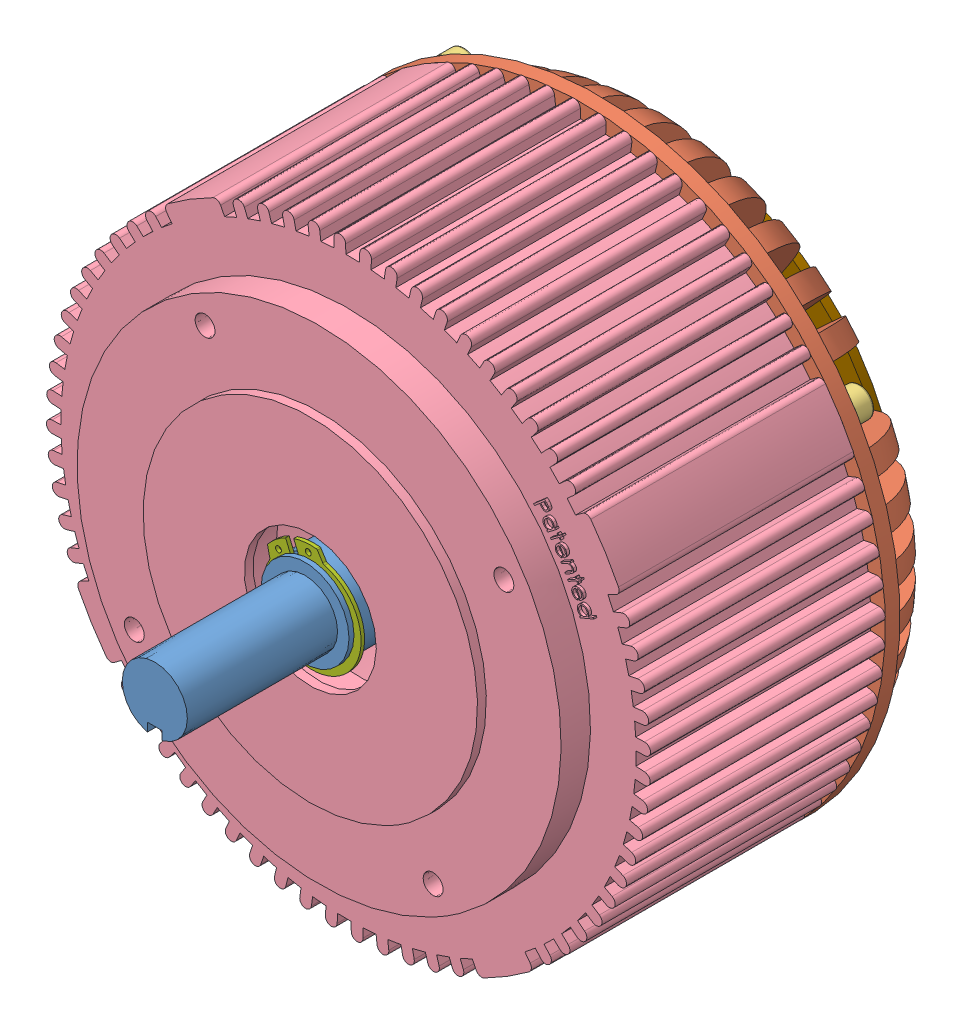
SolidWorks assembly （外形图）风冷图, configuration 默认. Lengths in mm.
Overall size (283.49 283.49 182).
24 component instances, 9 part files, 24 mates.
Components (placement in the parent):
- 普通轴-1: 普通轴 [默认] at (-0.2455 -4.4538 -85) size (35 35 168.2)
- 盖-1: 盖 [默认] at (-0.2455 -4.4538 -43.6) x (0.973109 -0.230344 0) z (0 0 -1) size (206 206 49.2)
- Hexagon socket head cap screws GB-5: Hexagon socket head cap screws GB [GB_FASTENER_SCREWS_HSHCS M8X16-N] at (-54.7076 -38.0675 -75.8) x (0 0 1) z (0.923728 0.383049 0) size (24 13 13)
- Hexagon socket head cap screws GB-6: Hexagon socket head cap screws GB [GB_FASTENER_SCREWS_HSHCS M8X16-N] at (-33.8592 50.0083 -75.8) x (0 0 1) z (0.383049 -0.923728 0) size (24 13 13)
- Hexagon socket head cap screws GB-7: Hexagon socket head cap screws GB [GB_FASTENER_SCREWS_HSHCS M8X16-N] at (54.2166 29.1599 -75.8) x (0 0 1) z (-0.923728 -0.383049 0) size (24 13 13)
- Hexagon socket head cap screws GB-8: Hexagon socket head cap screws GB [GB_FASTENER_SCREWS_HSHCS M8X16-N] at (33.3682 -58.9159 -75.8) x (0 0 1) z (-0.383049 0.923728 0) size (24 13 13)
- 机壳-1: 机壳 [默认] at (-0.2455 -4.4538 30.2) x (0.525214 -0.85097 0) z (0 0 -1) size (206 206 93)
- Hexagon socket head cap screws GB-10: Hexagon socket head cap screws GB [GB_FASTENER_SCREWS_HSHCS M6X16-N] at (51.2255 -87.8488 -73.8) x (0 0 1) z (0.923728 0.383049 0) size (22 10 10)
- Hexagon socket head cap screws GB-11: Hexagon socket head cap screws GB [GB_FASTENER_SCREWS_HSHCS M6X16-N] at (-83.6405 -55.9248 -73.8) x (0 0 1) z (0.383049 -0.923728 0) size (22 10 10)
- Hexagon socket head cap screws GB-12: Hexagon socket head cap screws GB [GB_FASTENER_SCREWS_HSHCS M6X16-N] at (-51.7165 78.9413 -73.8) x (0 0 1) z (-0.923728 -0.383049 0) size (22 10 10)
- Hexagon socket head cap screws GB-13: Hexagon socket head cap screws GB [GB_FASTENER_SCREWS_HSHCS M6X16-N] at (83.1496 47.0172 -73.8) x (0 0 1) z (-0.383049 0.923728 0) size (22 10 10)
- Prevailing torque type 2 GB-1: Prevailing torque type 2 GB [GB_HEXAGON_LOCK_TYPE10 M10-N] at (19.2694 -84.6125 -74.23) x (0.923728 0.383049 0) z (0 0 -1) size (18.48 16 12.8)
- Prevailing torque type 2 GB-2: Prevailing torque type 2 GB [GB_HEXAGON_LOCK_TYPE10 M10-N] at (-6.4561 -86.7197 -74.23) x (0.996886 0.078854 0) z (0 0 -1) size (18.48 16 12.8)
- Prevailing torque type 2 GB-3: Prevailing torque type 2 GB [GB_HEXAGON_LOCK_TYPE10 M10-N] at (-31.5737 -80.7741 -74.23) x (0.972462 -0.233061 0) z (0 0 -1) size (18.48 16 12.8)
- Prevailing torque type 2 GB-4: Prevailing torque type 2 GB [GB_HEXAGON_LOCK_TYPE10 M10-N] at (-53.6247 -67.3578 -74.23) x (0.852847 -0.522161 0) z (0 0 -1) size (18.48 16 12.8)
- Circlips for holes--Type A GB-1: Circlips for holes--Type A GB [GB_CONNECTING_PIECE_RING_RRH 52] at (-0.2455 -4.4538 -64.1) x (-0.923728 -0.383049 0) z (0 0 -1) size (56.2 54.06 2)
- Circlips for shaft--Type A large GB-1: Circlips for shaft--Type A large GB [GB_CONNECTING_PIECE_RING_RRA 30] at (0.1108 -5.3128 28.8) x (0.923728 0.383049 0) z (0 0 -1) size (33.5 36.57 1.2)
- Hexagon socket head cap screws GB-14: Hexagon socket head cap screws GB [GB_FASTENER_SCREWS_HSHCS M3X8-N] at (67.8722 -20.5779 -98.8) x (0 0 1) z (-1 0 0) size (11 5.5 5.5)
- 风页-1: 风页 [默认] at (-0.2455 -4.4538 -63.7) x (0 0 1) z (-1 0 0) size (25.28 108.45 96.5)
- 风页盖板-1: 风页盖板 [默认] at (-0.2455 -4.4538 -92.8) x (-0.230344 -0.973109 0) z (0 0 -1) size (150 150 3)
- Hexagon socket head cap screws GB-15: Hexagon socket head cap screws GB [GB_FASTENER_SCREWS_HSHCS M3X8-N] at (-16.3696 -72.5714 -98.8) x (0 0 1) z (0 1 0) size (11 5.5 5.5)
- Hexagon socket head cap screws GB-16: Hexagon socket head cap screws GB [GB_FASTENER_SCREWS_HSHCS M3X8-N] at (-68.3631 11.6703 -98.8) x (0 0 1) z (1 0 0) size (11 5.5 5.5)
- Hexagon socket head cap screws GB-17: Hexagon socket head cap screws GB [GB_FASTENER_SCREWS_HSHCS M3X8-N] at (15.8786 63.6639 -98.8) x (0 0 1) z (0 -1 0) size (11 5.5 5.5)
- Hexagon socket head cap screws GB-18: Hexagon socket head cap screws GB [GB_FASTENER_SCREWS_HSHCS M4X12-N] at (-18.3654 24.9047 7.2) x (0 0 1) z (-1 0 0) size (16 7 7)
Mates (geometry in assembly coordinates):
- 同心3: concentric anti-aligned: circle of 普通轴-1; circle of 盖-1
- 同心4: concentric anti-aligned: circle of 普通轴-1; circle of 盖-1
- 重合3: coincident aligned: plane of 普通轴-1 through (-0.2455 -4.4538 -45.6) normal (0 0 -1); plane of 盖-1 through (-0.2455 -4.4538 -45.6) normal (0 0 -1)
- 同心7: concentric aligned: cylinder of 盖-1 through (-54.7076 -38.0675 -43.6) axis (0 0 -1) radius 4.5; cylinder of Hexagon socket head cap screws GB-5 through (-54.7076 -38.0675 -51.8) axis (0 0 -1) radius 4
- 重合8: coincident anti-aligned: plane of 盖-1 through (51.9831 216.1904 -67.8) normal (0 0 -1); plane of Hexagon socket head cap screws GB-5 through (-54.7076 -38.0675 -67.8) normal (0 0 1)
- 同心9: concentric anti-aligned: circle of 盖-1; circle of 机壳-1
- 重合10: coincident anti-aligned: circle of 盖-1; plane of 机壳-1 through (-0.2455 -4.4538 -62.8) normal (0 0 -1)
- 同心10: concentric aligned: circle of 盖-1; circle of 机壳-1
- 同心13: concentric aligned: circle of 盖-1; circle of Hexagon socket head cap screws GB-10
- 重合16: coincident anti-aligned: plane of 盖-1 through (51.9831 216.1904 -67.8) normal (0 0 -1); plane of Hexagon socket head cap screws GB-10 through (51.2255 -87.8488 -67.8) normal (0 0 1)
- 同心15: concentric aligned: circle of 盖-1; circle of Prevailing torque type 2 GB-1
- 重合18: coincident anti-aligned: plane of 盖-1 through (51.9831 216.1904 -67.8) normal (0 0 -1); plane of Prevailing torque type 2 GB-1 through (20.4715 -75.4534 -67.8) normal (0 0 1)
- 重合19: coincident anti-aligned: plane of 盖-1 through (-0.2455 -4.4538 -62.1) normal (0 0 -1); plane of Circlips for holes--Type A GB-1 through (-0.2455 -4.4538 -62.1) normal (0 0 1)
- 同心18: concentric aligned: circle of 普通轴-1; circle of Circlips for shaft--Type A large GB-1
- 重合20: coincident anti-aligned: plane of 普通轴-1 through (-0.2455 -4.4538 28.8) normal (0 0 1); plane of Circlips for shaft--Type A large GB-1 through (-0.2455 -4.4538 28.8) normal (0 0 -1)
- 重合21: coincident aligned: circle of 普通轴-1; circle of 风页-1
- 同心19: concentric aligned: circle of 盖-1; circle of 风页盖板-1
- 重合22: coincident anti-aligned: plane of 盖-1 through (-0.2455 -4.4538 -92.8) normal (0 0 -1); plane of 风页盖板-1 through (-0.2455 -4.4538 -92.8) normal (0 0 1)
- 同心20: concentric aligned: circle of 盖-1; circle of 风页盖板-1
- 同心22: concentric anti-aligned: circle of Hexagon socket head cap screws GB-14; circle of 风页盖板-1
- 重合23: coincident anti-aligned: circle of Hexagon socket head cap screws GB-14; plane of 风页盖板-1 through (-0.2455 -4.4538 -95.8) normal (0 0 -1)
- 局部圆周阵列4: unknown: line of 盖-1 through (-0.2455 -4.4538 -67.8) axis (0 0 -1)
- 局部圆周阵列5: unknown: line of 盖-1 through (-0.2455 -4.4538 -67.8) axis (0 0 -1)
- 局部圆周阵列6: unknown: line of 风页盖板-1 through (-0.2455 -4.4538 -95.8) axis (0 0 -1)
